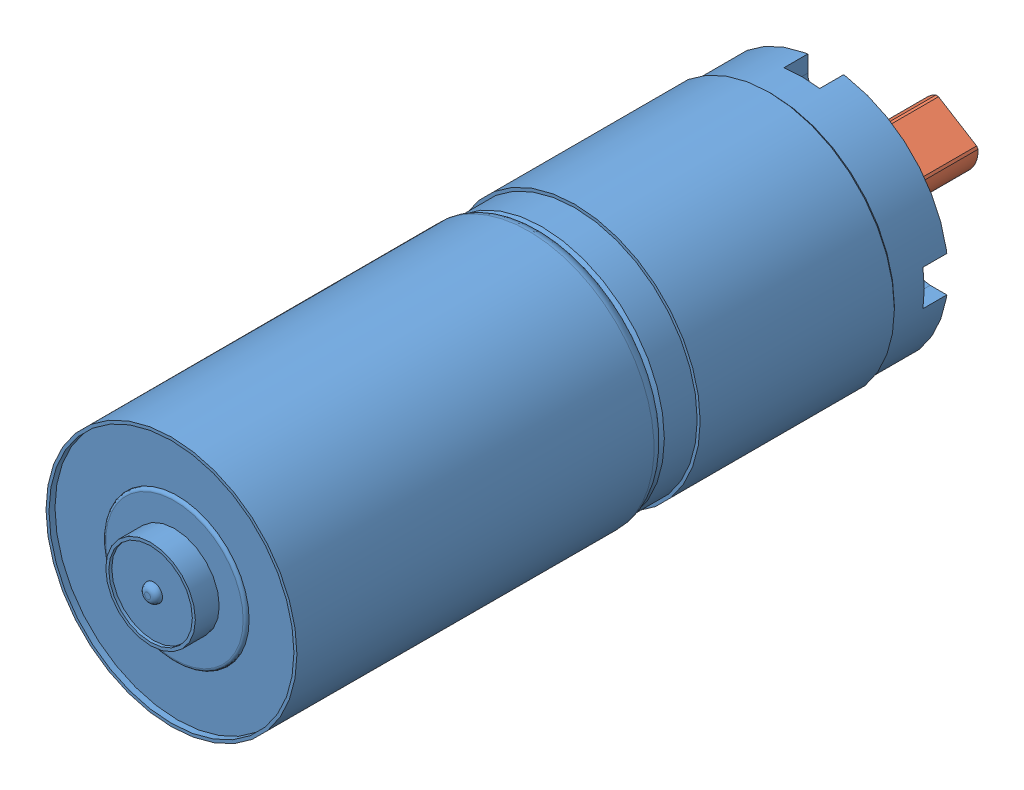
SolidWorks assembly 775 Motor, configuration Default. Lengths in mm.
Overall size (42 42 134).
2 component instances, 2 part files, 2 mates.
Components (placement in the parent):
- 1Nlocomotion 775_motor-1: 1Nlocomotion 775_motor [Default] at (45.037 64.6344 26.5191) size (42 42 115)
- 1Nshaft_775_motor-1: 1Nshaft_775_motor [Default] at (45.037 64.6344 7.5191) x (-0.525202 -0.850977 0) z (0 0 1) size (8 10 20)
Mates (geometry in assembly coordinates):
- Coincident1: coincident: plane of 1Nlocomotion 775_motor-1 through (45.037 64.6344 27.5191) normal (0 0 -1); plane of 1Nshaft_775_motor-1 through (45.037 64.6344 27.5191) normal (0 0 1)
- Concentric1: concentric: cylinder of 1Nlocomotion 775_motor-1 through (45.037 64.6344 70.0191) axis (0 0 -1) radius 21; cylinder of 1Nshaft_775_motor-1 through (45.037 64.6344 27.5191) axis (0 0 -1) radius 5
